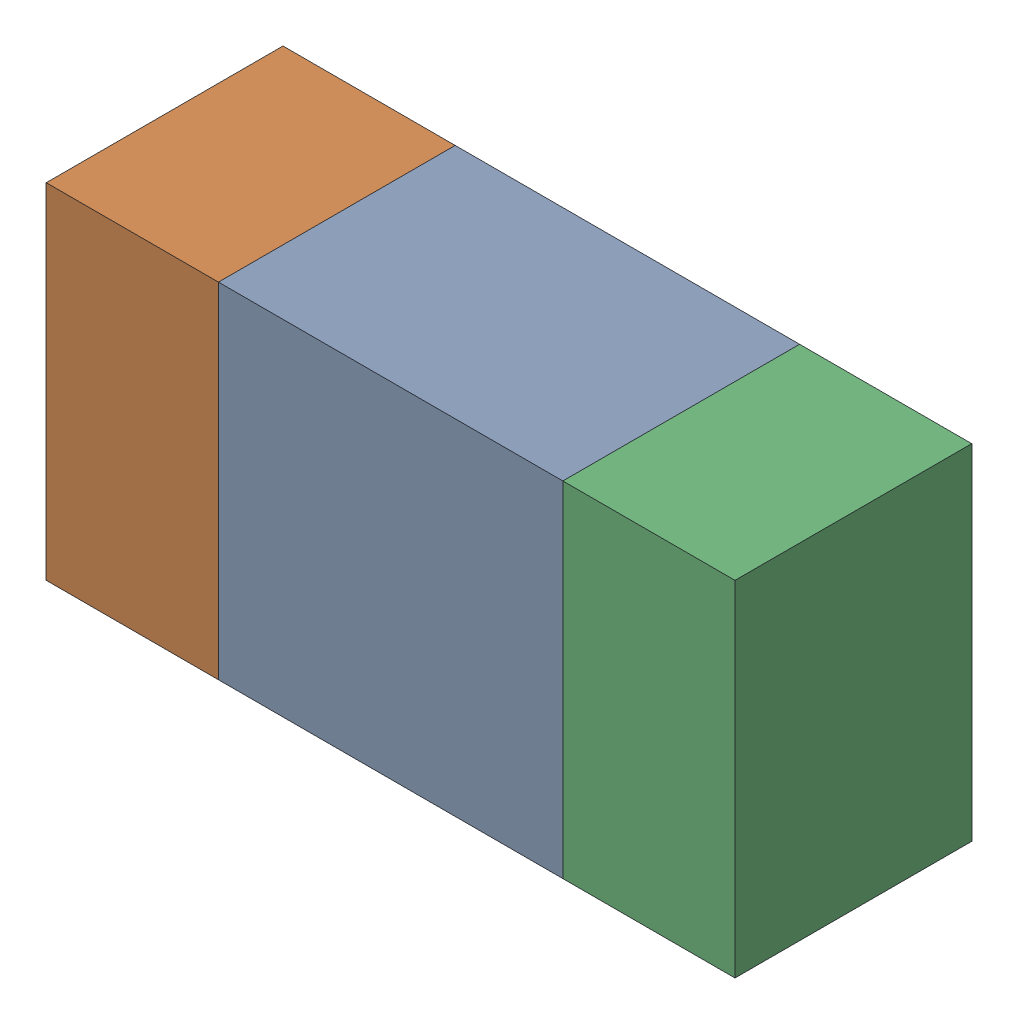
SolidWorks assembly R46, configuration ﾃﾞﾌｫﾙﾄ. Lengths in mm.
Overall size (1.6 0.8 0.55).
6 component instances, 2 part files, 0 mates.
Components (placement in the parent):
- 689261648-1: 689261648 [ﾃﾞﾌｫﾙﾄ] at (57.8 29.1999 0) size (0.8 0.8 0.55)
  - Extruded_33-1: Extruded_33 [ﾃﾞﾌｫﾙﾄ] at origin size (0.8 0.8 0.55)
- 689261512-1: 689261512 [ﾃﾞﾌｫﾙﾄ] at (57.1999 29.1999 0) size (0.4 0.8 0.55)
  - Extruded_32-1: Extruded_32 [ﾃﾞﾌｫﾙﾄ] at origin size (0.4 0.8 0.55)
- 689261512-2: 689261512 [ﾃﾞﾌｫﾙﾄ] at (58.3999 29.1999 0) size (0.4 0.8 0.55)
  - Extruded_32-1: Extruded_32 [ﾃﾞﾌｫﾙﾄ] at origin size (0.4 0.8 0.55)
